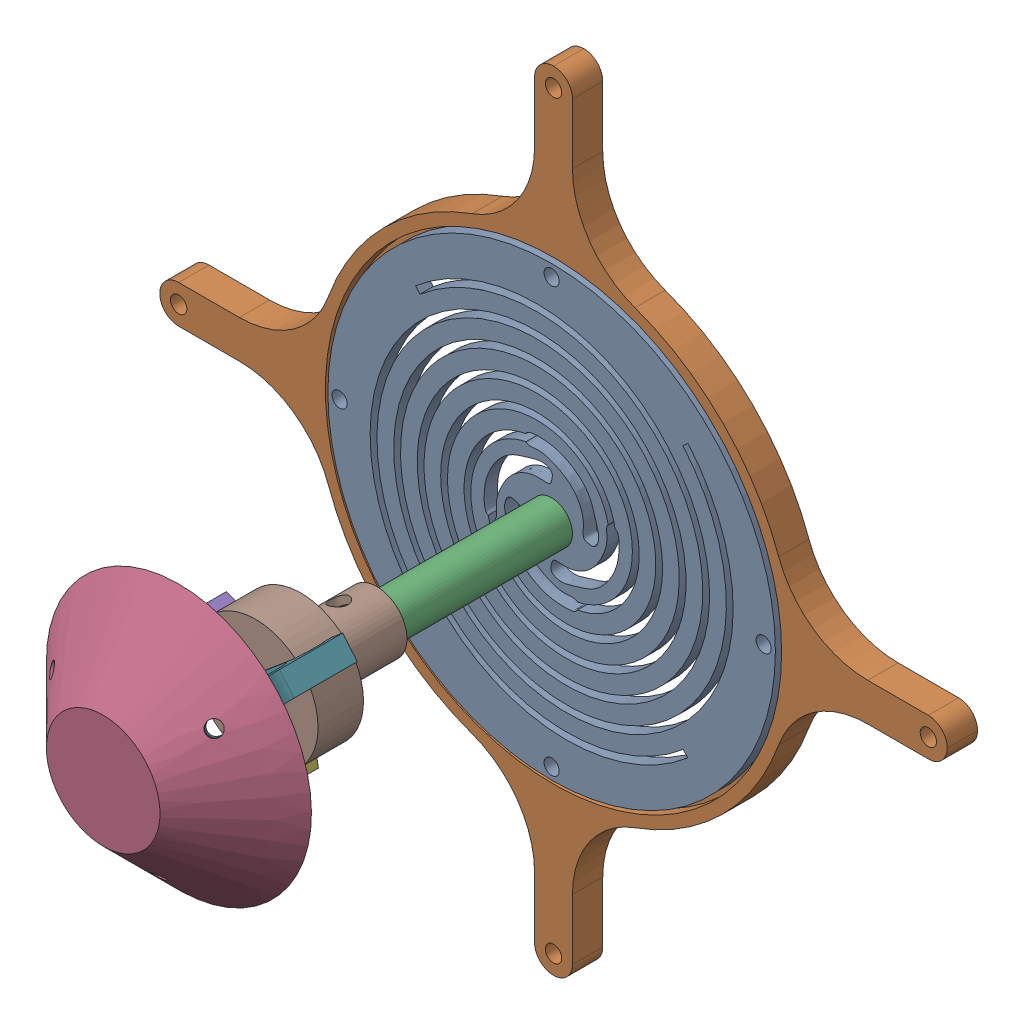
SolidWorks assembly SpiralAssembly, configuration Predeterminado. Lengths in mm.
Overall size (208 208 126.93).
8 component instances, 6 part files, 11 mates.
Components (placement in the parent):
- spiral-1: spiral [Predeterminado] at origin size (118.2 118.2 3.56) (hidden)
- FrameSpirals-ForLegs-1: FrameSpirals-ForLegs [Predeterminado] at (0 0 -5) size (208 208 8)
- tube-1: tube [Predeterminado] at (0 0 63.5) x (-0.698482 0.715628 0) z (0 0 -1) size (11 11 60)
- OscillatorSurface-1: OscillatorSurface [Predeterminado] at (0 0 121.933) x (0.939816 -0.341682 0) z (0.341682 0.939816 0) size (70 20 70)
- pata_oscillator-1: pata_oscillator [Predeterminado] at (-19.6959 3.7025 91.7432) x (0.939816 -0.341682 0) z (0 0 1) size (24.93 6 42)
- pata_oscillator-2: pata_oscillator [Predeterminado] at (6.6414 -18.9084 91.7432) x (-0.174002 0.984745 0) z (0 0 1) size (24.93 6 42)
- pata_oscillator-3: pata_oscillator [Predeterminado] at (13.0544 15.2058 91.7432) x (-0.765813 -0.643063 0) z (0 0 1) size (24.93 6 42)
- Support_Tube-1: Support_Tube [Predeterminado] at (0.0503 0.3687 81.7432) x (-0.643063 0.765813 0) z (-0.765813 -0.643063 0) size (33 32 33) (hidden)
Mates (geometry in assembly coordinates):
- Coincidente1: coincident anti-aligned: plane of spiral-1 through (0 0 0) normal (0 0 -1); plane of FrameSpirals-ForLegs-1 through (0 0 0) normal (0 0 1)
- Concéntrica1: concentric aligned: cylinder of spiral-1 through (0 56 3.5) axis (0 0 -1) radius 2; cylinder of FrameSpirals-ForLegs-1 through (0 56 0) axis (0 0 -1) radius 2
- Concéntrica3: concentric anti-aligned: cylinder of spiral-1 through (0 0 3.5) axis (0 0 -1) radius 4; cylinder of tube-1 through (0 0 3.5) axis (0 0 1) radius 5.5
- Coincidente2: coincident anti-aligned: plane of spiral-1 through (0 0 3.5) normal (0 0 1); plane of tube-1 through (0 0 3.5) normal (0 0 -1)
- Paralelo1: parallel aligned: plane of tube-1 through (0 0 63.5) normal (0 0 1); plane of OscillatorSurface-1 through (0 0 121.933) normal (0 0 1)
- Concéntrica4: concentric aligned: cylinder of tube-1 through (0 0 3.5) axis (0 0 1) radius 5.5; cone of OscillatorSurface-1 through (0 0 121.933) axis (0 0 1)
- Tangente2: tangent aligned: cone of OscillatorSurface-1 through (0 0 120.933) axis (0 0 1); plane of pata_oscillator-1 through (-28.9235 13.4416 103.7432) normal (-0.66455 0.241606 0.707107)
- Concéntrica8: concentric aligned: cylinder of OscillatorSurface-1 through (9.1466 -3.5914 76.7562) axis (-0.66455 0.241606 0.707107) radius 1.9; cylinder of pata_oscillator-1 through (-17.6854 6.1637 105.3064) axis (-0.66455 0.241606 0.707107) radius 1.9
- Concéntrica9: concentric anti-aligned: cylinder of pata_oscillator-3 through (8.0913 7.1208 89.2432) axis (0 0 -1) radius 1.95; cylinder of Support_Tube-1 through (8.0913 7.1208 69.7432) axis (0 0 1) radius 1.975
- Paralelo6: parallel anti-aligned: plane of pata_oscillator-3 through (16.9128 10.611 91.7432) normal (0.643063 -0.765813 0); plane of Support_Tube-1 through (14.6475 8.6435 79.1932) normal (-0.643063 0.765813 0)
- Coincidente9: coincident anti-aligned: plane of pata_oscillator-3 through (16.9128 10.611 71.7432) normal (0 0 -1); plane of Support_Tube-1 through (0.0503 0.3687 71.7432) normal (0 0 1)
